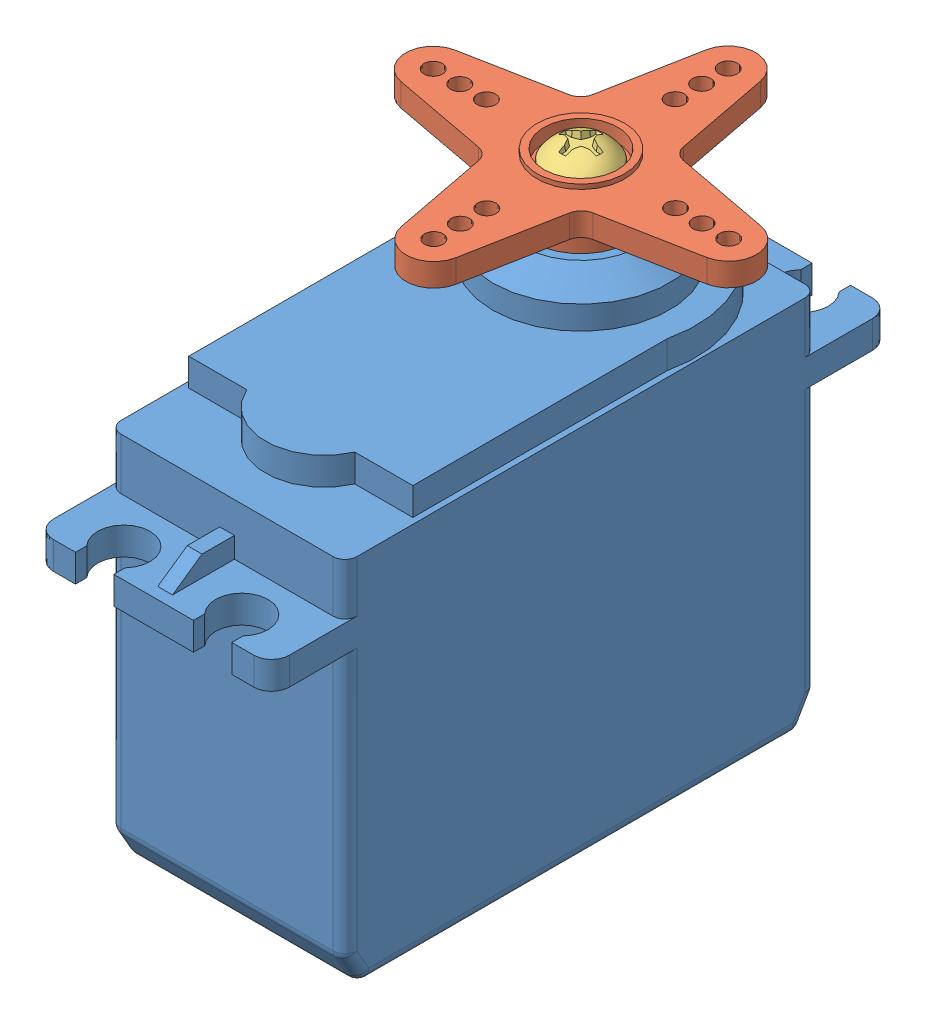
SolidWorks assembly servo_with_horn, configuration Default. Lengths in mm.
Overall size (30.22 43.6 53.29).
3 component instances, 3 part files, 4 mates.
Components (placement in the parent):
- servo-1: servo [Default] at (-20.1188 -18.8299 -0.7716) size (20.32 41.27 53.29)
- servohorn3-1: servohorn3 [Default] at (-20.1188 21.6514 -0.7716) x (0.999998 0 -0.001977) z (0.001977 0 0.999998) size (30.16 4.76 30.16)
- #4 Screw-1: #4 Screw [90935A131] at (-20.1188 22.842 -0.7716) x (1 0 0) z (0 1 0) size (5.56 5.56 8.28)
Mates (geometry in assembly coordinates):
- Coincident3: coincident anti-aligned: plane of servo-1 through (-20.1188 19.2701 -0.7716) normal (0 1 0); plane of servohorn3-1 through (-20.1188 19.2701 -0.7716) normal (0 -1 0)
- Concentric3: concentric anti-aligned: circle of servo-1; circle of servohorn3-1
- Coincident5: coincident anti-aligned: plane of servohorn3-1 through (-20.1188 22.842 -0.7716) normal (0 1 0); plane of #4 Screw-1 through (-20.1188 22.842 -0.7716) normal (0 -1 0)
- Concentric4: concentric anti-aligned: circle of servohorn3-1; circle of #4 Screw-1
